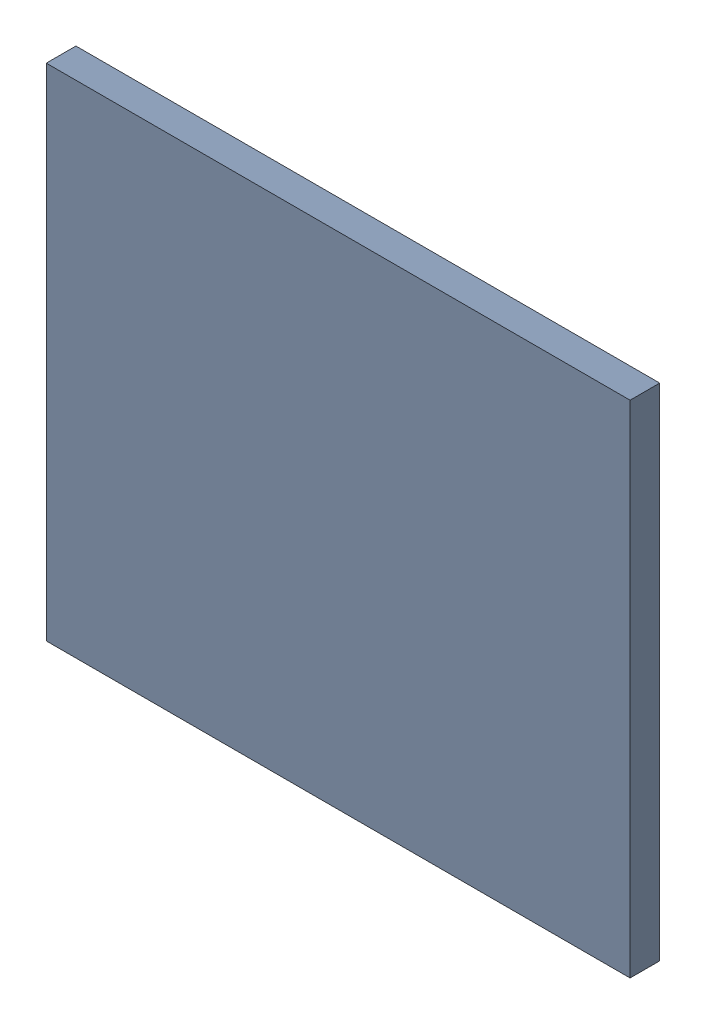
SolidWorks assembly Pad R3-2(31.05mm,41.5mm) on Top Layer, configuration Predeterminado. Lengths in mm.
Overall size (0.7 0.6 0.04).
2 component instances, 1 part files, 0 mates.
Components (placement in the parent):
- Pad R3-2(31.05mm,41.5mm) on Top Layer-1-1: Pad R3-2(31.05mm,41.5mm) on Top Layer-1 [Predeterminado] at (-68.317 -44.187 -0.0457) size (0.7 0.6 0.04)
  - Pad R3-2(31.05mm,41.5mm) on Top Layer-Part-1-1: Pad R3-2(31.05mm,41.5mm) on Top Layer-Part-1 [Predeterminado] at origin size (0.7 0.6 0.04)
